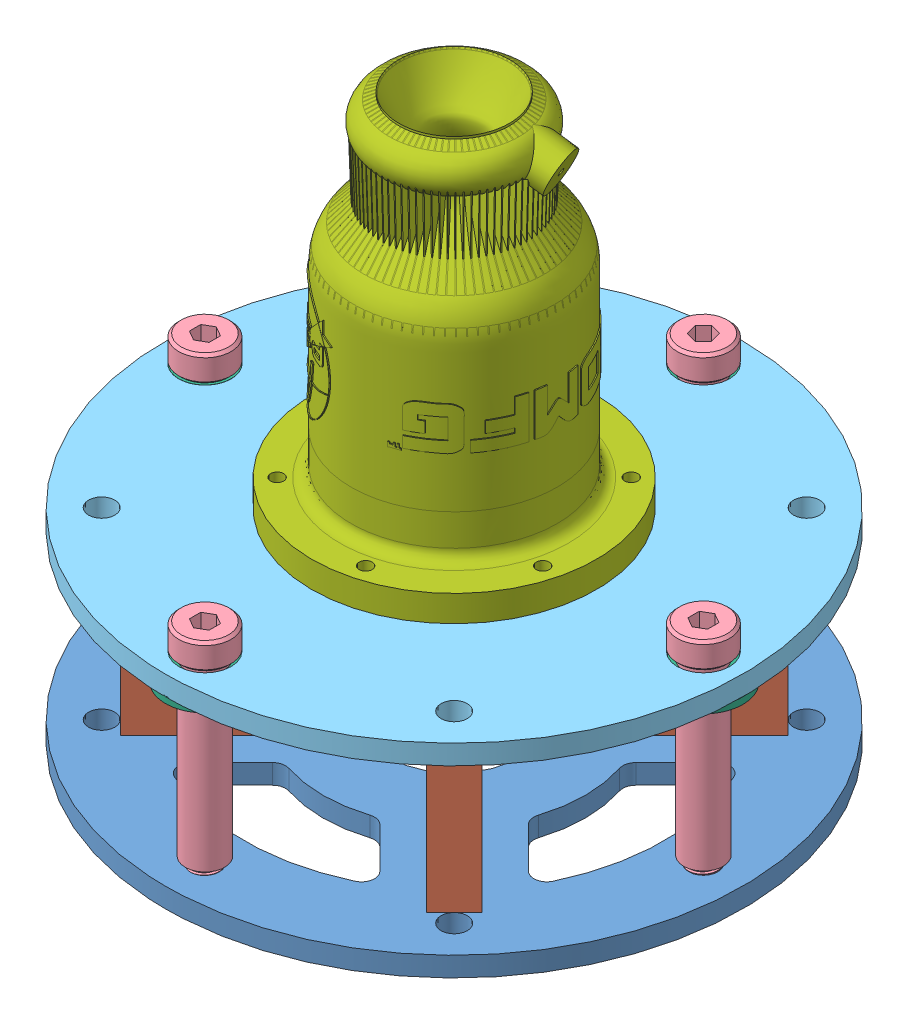
SolidWorks assembly load_cell_assembly_R2, configuration Default. Lengths in mm.
Overall size (304.8 272.91 304.8).
19 component instances, 7 part files, 26 mates.
Components (placement in the parent):
- load_cell_plate_R2-1: load_cell_plate_R2 [Default] at origin size (304.8 9.53 304.8)
- load_cell-1: load_cell [Default] at (74.0871 9.525 87.5575) x (0.707107 0 -0.707107) z (0.707107 0 0.707107) size (19.05 76.2 50.8)
- load_cell-2: load_cell [Default] at (87.5575 9.525 -74.0871) x (-0.707107 0 -0.707107) z (0.707107 0 -0.707107) size (19.05 76.2 50.8)
- load_cell-3: load_cell [Default] at (-87.5575 9.525 74.0871) x (0.707107 0 0.707107) z (-0.707107 0 0.707107) size (19.05 76.2 50.8)
- load_cell-5: load_cell [Default] at (-74.0871 9.525 -87.5575) x (-0.707107 0 0.707107) z (-0.707107 0 -0.707107) size (19.05 76.2 50.8)
- load_cell_ball_bearing-1: load_cell_ball_bearing [Default] at (-58.3717 84.1375 58.3717) size (9.53 9.53 9.53)
- load_cell_ball_bearing-2: load_cell_ball_bearing [Default] at (-58.3717 84.1375 -58.3717) size (9.53 9.53 9.53)
- load_cell_ball_bearing-3: load_cell_ball_bearing [Default] at (58.3717 84.1375 58.3717) size (9.53 9.53 9.53)
- load_cell_ball_bearing-4: load_cell_ball_bearing [Default] at (58.3717 84.1375 -58.3717) size (9.53 9.53 9.53)
- load_cell_guide-1: load_cell_guide [Default] at (0 111.125 120.65) x (-1 0 0) z (0 0 1) size (25.4 120.47 25.4)
- load_cell_guide-2: load_cell_guide [Default] at (0 111.125 -120.65) x (-0.252857 0 0.967504) z (0.967504 0 0.252857) size (25.4 120.47 25.4)
- load_cell_guide-3: load_cell_guide [Default] at (120.65 111.5409 0) x (-1 0 0) z (0 0 1) size (25.4 120.47 25.4)
- load_cell_guide-4: load_cell_guide [Default] at (-120.65 111.125 0) x (-1 0 0) z (0 0 1) size (25.4 120.47 25.4)
- load_cell_plate_mount_R2-1: load_cell_plate_mount_R2 [Default] at (0 88.9 0) size (304.8 9.53 304.8)
- load_cell_bushing-5: load_cell_bushing [Default] at (0 85.725 -120.65) size (38.1 9.53 38.1)
- load_cell_bushing-7: load_cell_bushing [Default] at (120.65 85.725 0) size (38.1 9.53 38.1)
- load_cell_bushing-8: load_cell_bushing [Default] at (-120.65 88.9569 0) size (38.1 9.53 38.1)
- load_cell_bushing-9: load_cell_bushing [Default] at (0 86.1161 120.65) size (38.1 9.53 38.1)
- Part_Engine_V1-1: Part_Engine_V1 [Default] at (-0.0001 250.5232 0) x (0.965926 0 -0.258819) z (0.258819 0 0.965926) size (137.73 174.49 137.73)
Mates (geometry in assembly coordinates):
- Coincident6: coincident: plane of load_cell_plate_R2-1 through (0 9.525 0) normal (0 1 0); plane of load_cell-1 through (87.5575 9.525 74.0871) normal (0 -1 0)
- Coincident7: coincident: plane of load_cell_plate_R2-1 through (0 9.525 0) normal (0 1 0); plane of load_cell-2 through (74.0871 9.525 -87.5575) normal (0 -1 0)
- Coincident8: coincident: plane of load_cell_plate_R2-1 through (0 9.525 0) normal (0 1 0); plane of load_cell-5 through (-87.5575 9.525 -74.0871) normal (0 -1 0)
- Coincident9: coincident: plane of load_cell_plate_R2-1 through (0 9.525 0) normal (0 1 0); plane of load_cell-3 through (-74.0871 9.525 87.5575) normal (0 -1 0)
- Concentric17: concentric: sphere of load_cell_ball_bearing-4; cylinder of load_cell-2 through (58.3717 81.0006 -58.3717) axis (0 1 0) radius 4.7244
- Concentric18: concentric: sphere of load_cell_ball_bearing-3; cylinder of load_cell-1 through (58.3717 81.0006 58.3717) axis (0 1 0) radius 4.7244
- Concentric19: concentric: sphere of load_cell_ball_bearing-1; cylinder of load_cell-3 through (-58.3717 81.0006 58.3717) axis (0 1 0) radius 4.7244
- Concentric20: concentric: sphere of load_cell_ball_bearing-2; cylinder of load_cell-5 through (-58.3717 81.0006 -58.3717) axis (0 1 0) radius 4.7244
- Concentric34: concentric: circle of load_cell_plate_R2-1; circle of load_cell-2
- Concentric35: concentric: circle of load_cell_plate_R2-1; circle of load_cell-2
- Concentric36: concentric: circle of load_cell_plate_R2-1; circle of load_cell-5
- Concentric37: concentric: circle of load_cell_plate_R2-1; circle of load_cell-5
- Concentric38: concentric: circle of load_cell_plate_R2-1; circle of load_cell-3
- Concentric39: concentric: circle of load_cell_plate_R2-1; circle of load_cell-3
- Concentric40: concentric: circle of load_cell_plate_R2-1; circle of load_cell-1
- Concentric41: concentric: circle of load_cell_plate_R2-1; circle of load_cell-1
- Concentric42: concentric: cylinder of load_cell_guide-1 through (0 0 120.65) axis (0 1 0) radius 9.525; cylinder of load_cell_bushing-9 through (0 86.1161 120.65) axis (0 1 0) radius 9.525
- Distance1: distance = 3.175 mm: plane of load_cell-1 through (87.5575 85.725 74.0871) normal (0 1 0); plane of load_cell_plate_mount_R2-1 through (0 88.9 0) normal (0 -1 0)
- Concentric45: concentric: circle of load_cell_plate_R2-1; circle of load_cell_plate_mount_R2-1
- Concentric46: concentric: cylinder of load_cell_plate_mount_R2-1 through (0 88.9 120.65) axis (0 1 0) radius 12.6746; cylinder of load_cell_bushing-9 through (0 95.6411 120.65) axis (0 -1 0) radius 12.7
- Concentric47: concentric: cylinder of load_cell_guide-4 through (-120.65 0 0) axis (0 1 0) radius 9.525; cylinder of load_cell_bushing-8 through (-120.65 88.9569 0) axis (0 1 0) radius 9.525
- Concentric48: concentric: circle of load_cell_plate_mount_R2-1; cylinder of load_cell_bushing-8 through (-120.65 98.4819 0) axis (0 -1 0) radius 12.7
- Concentric49: concentric: circle of load_cell_plate_mount_R2-1; cylinder of load_cell_bushing-7 through (120.65 85.725 0) axis (0 1 0) radius 9.525
- Concentric50: concentric: cylinder of load_cell_guide-3 through (120.65 0.4159 0) axis (0 1 0) radius 9.525; cylinder of load_cell_bushing-7 through (120.65 85.725 0) axis (0 1 0) radius 9.525
- Concentric51: concentric: cylinder of load_cell_plate_mount_R2-1 through (0 88.9 -120.65) axis (0 1 0) radius 12.6746; cylinder of load_cell_bushing-5 through (0 85.725 -120.65) axis (0 1 0) radius 9.525
- Concentric52: concentric: cylinder of load_cell_guide-2 through (0 0 -120.65) axis (0 1 0) radius 9.525; cylinder of load_cell_bushing-5 through (0 85.725 -120.65) axis (0 1 0) radius 9.525
